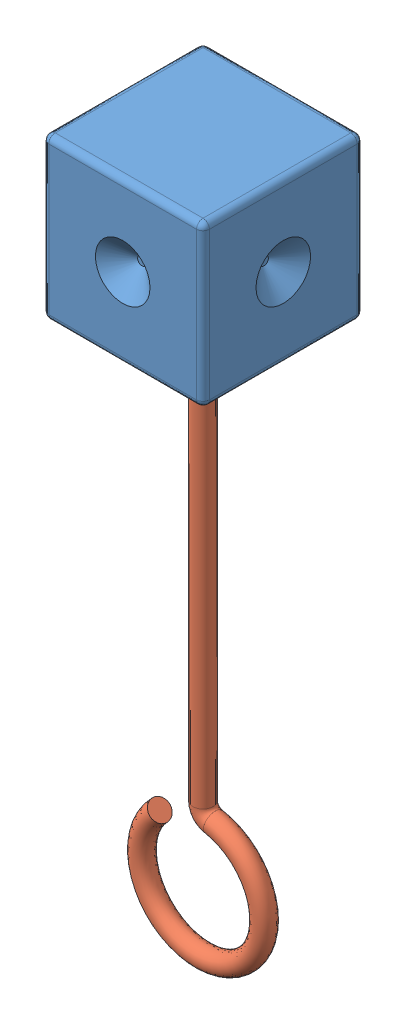
SolidWorks assembly Montagem2, configuration Valor predeterminado. Lengths in mm.
Overall size (25 112.48 25).
2 component instances, 2 part files, 2 mates.
Components (placement in the parent):
- Cubo_Gancho-1: Cubo_Gancho [Default] at (9.4439 8.3021 12.5) size (25 25 25)
- gancho-1: gancho [Valor predeterminado] at (-1.8556 -11.8758 25) x (1 0 0) z (0 1 0) size (22.19 3.17 87.48)
Mates (geometry in assembly coordinates):
- Concêntrico1: concentric: circle of assembly; circle of assembly; circle of Cubo_Gancho-1; circle of gancho-1
- Coincidente1: coincident: plane of assembly; plane of assembly; plane of Cubo_Gancho-1 through (-14.3556 -11.8758 37.5) normal (0 -1 0); plane of gancho-1 through (-1.8556 -11.8758 25) normal (0 1 0)
